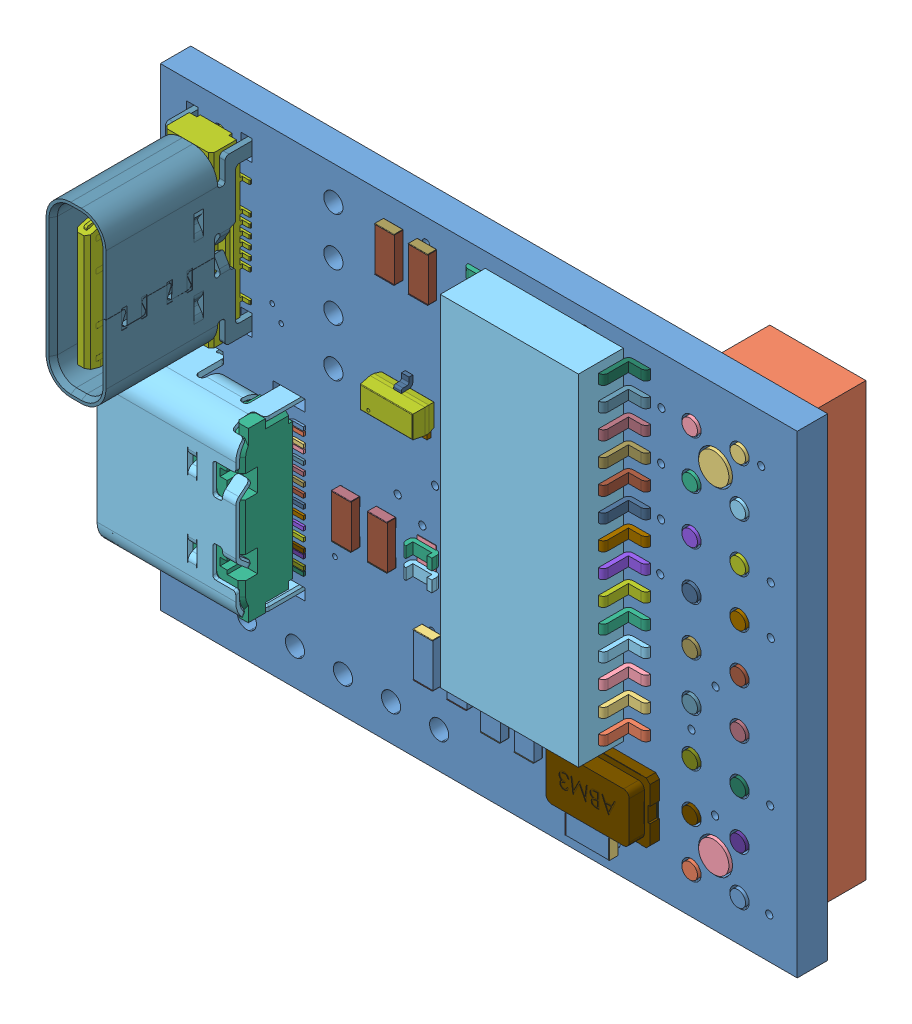
SolidWorks assembly pic backpack, configuration Default. Lengths in mm.
Overall size (33.69 32.08 21.86).
214 component instances, 150 part files, 0 mates.
Components (placement in the parent):
- Layer_1-1: Layer_1 [Predeterminado] at origin size (33.66 25.02 1.61)
- J1-1: J1 [Predeterminado] at (-14.605 24.638 -0.803) x (0 -1 0) z (0 0 -1) size (22.86 7.4 5.5)
  - Open CASCADE STEP translator 6.8 1.2.1-1: Open CASCADE STEP translator 6.8 1.2.1 [Predeterminado] at origin size (22.86 7.4 5.5)
    - Body_1-1: Body_1 [Predeterminado] at origin size (22.86 7.4 5.5)
      - =_[0_1_1_2]-1: =_[0_1_1_2] [Predeterminado] at (0 0 0.1) size (22.86 5.08 3.7)
      - =_[0_1_1_3]-1: =_[0_1_1_3] [Predeterminado] at origin size (21.14 7.4 0.1)
        - SOLID-1: SOLID [Predeterminado] at origin size (0.82 1.58 0.1)
        - SOLID_2-1: SOLID_2 [Predeterminado] at origin size (0.82 1.58 0.1)
        - SOLID_3-1: SOLID_3 [Predeterminado] at origin size (0.82 1.58 0.1)
        - SOLID_4-1: SOLID_4 [Predeterminado] at origin size (0.82 1.58 0.1)
        - SOLID_5-1: SOLID_5 [Predeterminado] at origin size (0.82 1.58 0.1)
        - SOLID_6-1: SOLID_6 [Predeterminado] at origin size (0.82 1.58 0.1)
        - SOLID_7-1: SOLID_7 [Predeterminado] at origin size (0.82 1.58 0.1)
        - SOLID_8-1: SOLID_8 [Predeterminado] at origin size (0.82 1.58 0.1)
        - SOLID_9-1: SOLID_9 [Predeterminado] at origin size (0.82 1.58 0.1)
        - SOLID_10-1: SOLID_10 [Predeterminado] at origin size (0.82 1.58 0.1)
        - SOLID_11-1: SOLID_11 [Predeterminado] at origin size (0.82 1.58 0.1)
        - SOLID_12-1: SOLID_12 [Predeterminado] at origin size (0.82 1.58 0.1)
        - SOLID_13-1: SOLID_13 [Predeterminado] at origin size (0.82 1.58 0.1)
        - SOLID_14-1: SOLID_14 [Predeterminado] at origin size (0.82 1.58 0.1)
        - SOLID_15-1: SOLID_15 [Predeterminado] at origin size (0.82 1.58 0.1)
        - SOLID_16-1: SOLID_16 [Predeterminado] at origin size (0.82 1.58 0.1)
        - SOLID_17-1: SOLID_17 [Predeterminado] at origin size (0.82 1.58 0.1)
        - SOLID_18-1: SOLID_18 [Predeterminado] at origin size (0.82 1.58 0.1)
      - =_[0_1_1_4]-1: =_[0_1_1_4] [Predeterminado] at origin size (21.14 3.36 1.8)
        - SOLID_19-1: SOLID_19 [Predeterminado] at origin size (0.82 0.82 1.8)
        - SOLID_20-1: SOLID_20 [Predeterminado] at origin size (0.82 0.82 1.8)
        - SOLID_21-1: SOLID_21 [Predeterminado] at origin size (0.82 0.82 1.8)
        - SOLID_22-1: SOLID_22 [Predeterminado] at origin size (0.82 0.82 1.8)
        - SOLID_23-1: SOLID_23 [Predeterminado] at origin size (0.82 0.82 1.8)
        - SOLID_24-1: SOLID_24 [Predeterminado] at origin size (0.82 0.82 1.8)
        - SOLID_25-1: SOLID_25 [Predeterminado] at origin size (0.82 0.82 1.8)
        - SOLID_26-1: SOLID_26 [Predeterminado] at origin size (0.82 0.82 1.8)
        - SOLID_27-1: SOLID_27 [Predeterminado] at origin size (0.82 0.82 1.8)
        - SOLID_28-1: SOLID_28 [Predeterminado] at origin size (0.82 0.82 1.8)
        - SOLID_29-1: SOLID_29 [Predeterminado] at origin size (0.82 0.82 1.8)
        - SOLID_30-1: SOLID_30 [Predeterminado] at origin size (0.82 0.82 1.8)
        - SOLID_31-1: SOLID_31 [Predeterminado] at origin size (0.82 0.82 1.8)
        - SOLID_32-1: SOLID_32 [Predeterminado] at origin size (0.82 0.82 1.8)
        - SOLID_33-1: SOLID_33 [Predeterminado] at origin size (0.82 0.82 1.8)
        - SOLID_34-1: SOLID_34 [Predeterminado] at origin size (0.82 0.82 1.8)
        - SOLID_35-1: SOLID_35 [Predeterminado] at origin size (0.82 0.82 1.8)
        - SOLID_36-1: SOLID_36 [Predeterminado] at origin size (0.82 0.82 1.8)
        - SOLID_37-1: SOLID_37 [Predeterminado] at origin size (1.6 1.6 1.8)
        - SOLID_38-1: SOLID_38 [Predeterminado] at origin size (1.6 1.6 1.8)
- U1-1: U1 [Predeterminado] at (-27.559 28.448 0.803) size (9.65 18 2.64)
  - Open CASCADE STEP translator 6.8 1.3.1-1: Open CASCADE STEP translator 6.8 1.3.1 [Predeterminado] at origin size (9.65 18 2.64)
    - Body_1-1: Body_1 [Predeterminado] at origin size (7.3 18 2.38)
    - Pin_1-1: Pin_1 [Predeterminado] at origin size (1.17 0.51 1.58)
    - Pin_2-1: Pin_2 [Predeterminado] at origin size (1.17 0.51 1.58)
    - Pin_3-1: Pin_3 [Predeterminado] at origin size (1.17 0.51 1.58)
    - Pin_4-1: Pin_4 [Predeterminado] at origin size (1.17 0.51 1.58)
    - Pin_5-1: Pin_5 [Predeterminado] at origin size (1.17 0.51 1.58)
    - Pin_6-1: Pin_6 [Predeterminado] at origin size (1.17 0.51 1.58)
    - Pin_7-1: Pin_7 [Predeterminado] at origin size (1.17 0.51 1.58)
    - Pin_8-1: Pin_8 [Predeterminado] at origin size (1.17 0.51 1.58)
    - Pin_9-1: Pin_9 [Predeterminado] at origin size (1.17 0.51 1.58)
    - Pin_10-1: Pin_10 [Predeterminado] at origin size (1.17 0.51 1.58)
    - Pin_11-1: Pin_11 [Predeterminado] at origin size (1.17 0.51 1.58)
    - Pin_12-1: Pin_12 [Predeterminado] at origin size (1.17 0.51 1.58)
    - Pin_13-1: Pin_13 [Predeterminado] at origin size (1.17 0.51 1.58)
    - Pin_14-1: Pin_14 [Predeterminado] at origin size (1.17 0.51 1.58)
    - Pin_15-1: Pin_15 [Predeterminado] at (18.8 -17.78 0) x (-1 0 0) z (0 0 1) size (1.17 0.51 1.58)
    - Pin_16-1: Pin_16 [Predeterminado] at (18.8 -15.24 0) x (-1 0 0) z (0 0 1) size (1.17 0.51 1.58)
    - Pin_17-1: Pin_17 [Predeterminado] at (18.8 -12.7 0) x (-1 0 0) z (0 0 1) size (1.17 0.51 1.58)
    - Pin_18-1: Pin_18 [Predeterminado] at (18.8 -10.16 0) x (-1 0 0) z (0 0 1) size (1.17 0.51 1.58)
    - Pin_19-1: Pin_19 [Predeterminado] at (18.8 -7.62 0) x (-1 0 0) z (0 0 1) size (1.17 0.51 1.58)
    - Pin_20-1: Pin_20 [Predeterminado] at (18.8 -5.08 0) x (-1 0 0) z (0 0 1) size (1.17 0.51 1.58)
    - Pin_21-1: Pin_21 [Predeterminado] at (18.8 -2.54 0) x (-1 0 0) z (0 0 1) size (1.17 0.51 1.58)
    - Pin_22-1: Pin_22 [Predeterminado] at (18.8 0 0) x (-1 0 0) z (0 0 1) size (1.17 0.51 1.58)
    - Pin_23-1: Pin_23 [Predeterminado] at (18.8 2.54 0) x (-1 0 0) z (0 0 1) size (1.17 0.51 1.58)
    - Pin_24-1: Pin_24 [Predeterminado] at (18.8 5.08 0) x (-1 0 0) z (0 0 1) size (1.17 0.51 1.58)
    - Pin_25-1: Pin_25 [Predeterminado] at (18.8 7.62 0) x (-1 0 0) z (0 0 1) size (1.17 0.51 1.58)
    - Pin_26-1: Pin_26 [Predeterminado] at (18.8 10.16 0) x (-1 0 0) z (0 0 1) size (1.17 0.51 1.58)
    - Pin_27-1: Pin_27 [Predeterminado] at (18.8 12.7 0) x (-1 0 0) z (0 0 1) size (1.17 0.51 1.58)
    - Pin_28-1: Pin_28 [Predeterminado] at (18.8 15.24 0) x (-1 0 0) z (0 0 1) size (1.17 0.51 1.58)
- U2-1: U2 [Predeterminado] at (-20.066 16.383 0.803) x (-1 0 0) z (0 0 1) size (5 3.22 1.3)
  - Open CASCADE STEP translator 6.8 1.4.1-1: Open CASCADE STEP translator 6.8 1.4.1 [Predeterminado] at origin size (5 3.22 1.3)
    - Body_1_2-1: Body_1_2 [Predeterminado] at (0 0 0.25) x (1 0 0) z (0 -1 0) size (5 1.3 3.22)
      - =_[0_1_1_3]-1: =_[0_1_1_3] [Predeterminado] at origin size (1.25 0.05 2)
      - =_[0_1_1_4]-1: =_[0_1_1_4] [Predeterminado] at origin size (1.25 0.05 2)
      - =_[0_1_1_5]-1: =_[0_1_1_5] [Predeterminado] at origin size (5 1.3 3.22)
- C2-1: C2 [Predeterminado] at (-26.035 17.907 0.803) x (0 -1 0) z (0 0 1) size (2.34 1.04 0.5)
  - Open CASCADE STEP translator 6.8 1.5.1-1: Open CASCADE STEP translator 6.8 1.5.1 [Predeterminado] at origin size (2.34 1.04 0.5)
    - Body_1_2-1: Body_1_2 [Predeterminado] at origin size (2.29 1.04 0.43)
    - Pin_1_2-1: Pin_1_2 [Predeterminado] at (0.3048 0 0) x (-1 0 0) z (0 0 1) size (0.51 1.02 0.5)
    - Pin_2_2-1: Pin_2_2 [Predeterminado] at origin size (0.51 1.02 0.5)
- C4-1: C4 [Predeterminado] at (-29.591 16.383 0.803) x (0 1 0) z (0 0 1) size (2.34 1.04 0.5)
  - Open CASCADE STEP translator 6.8 1.5.1-1: Open CASCADE STEP translator 6.8 1.5.1 [Predeterminado] at origin size (2.34 1.04 0.5)
    - Body_1_2-1: Body_1_2 [Predeterminado] at origin size (2.29 1.04 0.43)
    - Pin_1_2-1: Pin_1_2 [Predeterminado] at (0.3048 0 0) x (-1 0 0) z (0 0 1) size (0.51 1.02 0.5)
    - Pin_2_2-1: Pin_2_2 [Predeterminado] at origin size (0.51 1.02 0.5)
- C5-1: C5 [Predeterminado] at (-21.971 13.716 0.803) size (2.34 1.04 0.5)
  - Open CASCADE STEP translator 6.8 1.5.1-1: Open CASCADE STEP translator 6.8 1.5.1 [Predeterminado] at origin size (2.34 1.04 0.5)
    - Body_1_2-1: Body_1_2 [Predeterminado] at origin size (2.29 1.04 0.43)
    - Pin_1_2-1: Pin_1_2 [Predeterminado] at (0.3048 0 0) x (-1 0 0) z (0 0 1) size (0.51 1.02 0.5)
    - Pin_2_2-1: Pin_2_2 [Predeterminado] at origin size (0.51 1.02 0.5)
- C1-1: C1 [Predeterminado] at (-24.257 17.8816 0.803) x (0 -1 0) z (0 0 1) size (2.34 1.04 0.5)
  - Open CASCADE STEP translator 6.8 1.5.1-1: Open CASCADE STEP translator 6.8 1.5.1 [Predeterminado] at origin size (2.34 1.04 0.5)
    - Body_1_2-1: Body_1_2 [Predeterminado] at origin size (2.29 1.04 0.43)
    - Pin_1_2-1: Pin_1_2 [Predeterminado] at (0.3048 0 0) x (-1 0 0) z (0 0 1) size (0.51 1.02 0.5)
    - Pin_2_2-1: Pin_2_2 [Predeterminado] at origin size (0.51 1.02 0.5)
- C3-1: C3 [Predeterminado] at (-27.813 16.383 0.803) x (0 1 0) z (0 0 1) size (2.34 1.04 0.5)
  - Open CASCADE STEP translator 6.8 1.5.1-1: Open CASCADE STEP translator 6.8 1.5.1 [Predeterminado] at origin size (2.34 1.04 0.5)
    - Body_1_2-1: Body_1_2 [Predeterminado] at origin size (2.29 1.04 0.43)
    - Pin_1_2-1: Pin_1_2 [Predeterminado] at (0.3048 0 0) x (-1 0 0) z (0 0 1) size (0.51 1.02 0.5)
    - Pin_2_2-1: Pin_2_2 [Predeterminado] at origin size (0.51 1.02 0.5)
- JP1-1: JP1 [Predeterminado] at (-29.845 21.082 0.803) x (0 1 0) z (0 0 1) size (2 1.5 0.63)
  - Open CASCADE STEP translator 6.8 1.11.1-1: Open CASCADE STEP translator 6.8 1.11.1 [Predeterminado] at origin size (2 1.5 0.63)
    - Body_1_4-1: Body_1_4 [Predeterminado] at origin size (2 1 0.03)
    - Pin_1_3-1: Pin_1_3 [Predeterminado] x (0 1 0) z (0 0 1) size (1.5 0.59 0.63)
    - Pin_2_3-1: Pin_2_3 [Predeterminado] at (1 -1 0) x (0 1 0) z (0 0 1) size (1.5 0.59 0.63)
- Q1-1: Q1 [Predeterminado] at (-30.8 28.559 0.803) x (0 1 0) z (0 0 1) size (2.4 2.9 1.2)
  - Open CASCADE STEP translator 6.8 1.12.1-1: Open CASCADE STEP translator 6.8 1.12.1 [Predeterminado] at origin size (2.4 2.9 1.2)
    - Body_1_3-1: Body_1_3 [Predeterminado] at origin size (2.4 2.9 1.2)
      - =_[0_1_1_2]_2-1: =_[0_1_1_2]_2 [Predeterminado] at origin size (1.3 2.9 1.15)
      - =_[0_1_1_3]_2-1: =_[0_1_1_3]_2 [Predeterminado] at origin size (0.55 2.3 0.61)
        - SOLID_39-1: SOLID_39 [Predeterminado] at origin size (0.55 0.4 0.61)
        - SOLID_40-1: SOLID_40 [Predeterminado] at origin size (0.55 0.4 0.61)
      - =_[0_1_1_4]_2-1: =_[0_1_1_4]_2 [Predeterminado] at origin size (0.55 0.4 0.61)
- R1-1: R1 [Predeterminado] at (-29.845 36.0426 0.803) x (0 -1 0) z (0 0 1) size (2.34 1.04 0.5)
  - Open CASCADE STEP translator 6.8 1.13.1-1: Open CASCADE STEP translator 6.8 1.13.1 [Predeterminado] at origin size (2.34 1.04 0.5)
    - Body_1_5-1: Body_1_5 [Predeterminado] at origin size (2.29 1.04 0.43)
    - Pin_1_4-1: Pin_1_4 [Predeterminado] at (0.3048 0 0) x (-1 0 0) z (0 0 1) size (0.51 1.02 0.5)
    - Pin_2_4-1: Pin_2_4 [Predeterminado] at origin size (0.51 1.02 0.5)
- R2-1: R2 [Predeterminado] at (-31.623 36.068 0.803) x (0 -1 0) z (0 0 1) size (2.34 1.04 0.5)
  - Open CASCADE STEP translator 6.8 1.13.1-1: Open CASCADE STEP translator 6.8 1.13.1 [Predeterminado] at origin size (2.34 1.04 0.5)
    - Body_1_5-1: Body_1_5 [Predeterminado] at origin size (2.29 1.04 0.43)
    - Pin_1_4-1: Pin_1_4 [Predeterminado] at (0.3048 0 0) x (-1 0 0) z (0 0 1) size (0.51 1.02 0.5)
    - Pin_2_4-1: Pin_2_4 [Predeterminado] at origin size (0.51 1.02 0.5)
- J4-1: J4 [Predeterminado] at (-39.3381 34.5271 0.803) x (0 -1 0) z (0 0 1) size (30.95 12.2 21.86)
  - Open CASCADE STEP translator 6.8 1.15.1-1: Open CASCADE STEP translator 6.8 1.15.1 [Predeterminado] at origin size (30.95 12.2 21.86)
    - Body_1_4-1: Body_1_4 [Predeterminado] at (2.8 -2.8 0.11) x (1 0 0) z (0 -1 0) size (30.95 21.86 12.2)
      - Imported-1: Imported [Predeterminado] at (22 -7.19 8.4402) x (-1 0 0) z (0 0.000001 1) size (8.94 8.16 3.49)
      - Imported-2: Imported [Predeterminado] at (72.395 48.5033 -3.3613) x (1 0 0) z (0 1 -0.000001) size (8.94 3.77 7.85)
        - SHELL-1: SHELL [Predeterminado] at origin size (0.19 0.16 0.35)
        - SHELL_2-1: SHELL_2 [Predeterminado] at origin size (0.26 0.3 0.35)
        - SHELL_3-1: SHELL_3 [Predeterminado] at origin size (0.26 0.31 0.35)
        - SHELL_4-1: SHELL_4 [Predeterminado] at origin size (0.3 0.16 0.3)
        - SHELL_5-1: SHELL_5 [Predeterminado] at origin size (0.3 0.16 0.3)
        - SHELL_6-1: SHELL_6 [Predeterminado] at origin size (0.48 0.17 0.48)
        - SHELL_7-1: SHELL_7 [Predeterminado] at origin size (0.48 0.17 0.48)
        - SHELL_8-1: SHELL_8 [Predeterminado] at origin size (0.16 0.5 0.5)
        - SHELL_9-1: SHELL_9 [Predeterminado] at origin size (0.16 0.5 0.5)
        - SHELL_10-1: SHELL_10 [Predeterminado] at origin size (0.19 0.16 0.35)
        - ASSEMBLY-1: ASSEMBLY [Predeterminado] at origin size (8.94 3.77 7.85)
          - SHELL_11-1: SHELL_11 [Predeterminado] at origin size (8.94 3.77 7.85)
          - SHELL_12-1: SHELL_12 [Predeterminado] at origin size (0.2 0.01 0)
          - SHELL_13-1: SHELL_13 [Predeterminado] at origin size (0.2 0.01 0)
          - SHELL_14-1: SHELL_14 [Predeterminado] at origin size (0.2 0.01 0)
        - SHELL_16-1: SHELL_16 [Predeterminado] at origin size (0.21 0.01 0.02)
        - SHELL_17-1: SHELL_17 [Predeterminado] at origin size (0.2 0 0.01)
        - SHELL_18-1: SHELL_18 [Predeterminado] at origin size (0.2 0.1 0.1)
        - SHELL_19-1: SHELL_19 [Predeterminado] at origin size (0.2 0.1 0.1)
        - SHELL_20-1: SHELL_20 [Predeterminado] at origin size (0.2 0.1 0.1)
        - SHELL_21-1: SHELL_21 [Predeterminado] at origin size (0.2 0.1 0.1)
- J5-1: J5 [Predeterminado] at (-36.576 24.384 0.803) x (0 -1 0) z (0 0 1) size (8.94 7.71 4.41)
  - Open CASCADE STEP translator 6.8 1.16.1-1: Open CASCADE STEP translator 6.8 1.16.1 [Predeterminado] at origin size (8.94 7.71 4.41)
    - Body_1_5-1: Body_1_5 [Predeterminado] at (3.2 -4.8 0) x (1 0 0) z (0 -1 0) size (8.94 4.41 7.71)
      - Imported_2-1: Imported_2 [Predeterminado] at (0 0 -1.255) size (8.94 4.41 7.71)
        - SOLID_41-1: SOLID_41 [Predeterminado] at origin size (0.25 0.05 2.38)
        - SOLID_42-1: SOLID_42 [Predeterminado] at origin size (0.25 0.05 2.38)
        - SOLID_43-1: SOLID_43 [Predeterminado] at origin size (0.25 0.05 1.88)
        - SOLID_44-1: SOLID_44 [Predeterminado] at origin size (0.25 0.05 1.88)
        - SOLID_45-1: SOLID_45 [Predeterminado] at origin size (0.25 0.05 1.88)
        - SOLID_46-1: SOLID_46 [Predeterminado] at origin size (0.25 0.05 1.88)
        - SOLID_47-1: SOLID_47 [Predeterminado] at origin size (0.25 0.05 1.88)
        - SOLID_48-1: SOLID_48 [Predeterminado] at origin size (0.25 0.05 1.88)
        - SOLID_49-1: SOLID_49 [Predeterminado] at origin size (0.25 0.05 1.88)
        - SOLID_50-1: SOLID_50 [Predeterminado] at origin size (0.25 0.05 1.88)
        - SOLID_51-1: SOLID_51 [Predeterminado] at origin size (0.25 0.05 2.38)
        - SOLID_52-1: SOLID_52 [Predeterminado] at origin size (0.25 0.05 2.38)
        - SOLID_53-1: SOLID_53 [Predeterminado] at origin size (0.25 0.05 2.38)
        - SOLID_54-1: SOLID_54 [Predeterminado] at origin size (0.25 0.05 1.88)
        - SOLID_55-1: SOLID_55 [Predeterminado] at origin size (0.25 0.05 1.88)
        - SOLID_56-1: SOLID_56 [Predeterminado] at origin size (0.25 0.05 2.38)
        - SOLID_57-1: SOLID_57 [Predeterminado] at origin size (0.25 0.05 1.88)
        - SOLID_58-1: SOLID_58 [Predeterminado] at origin size (0.25 0.05 1.88)
        - SOLID_59-1: SOLID_59 [Predeterminado] at origin size (0.25 0.05 1.88)
        - SOLID_60-1: SOLID_60 [Predeterminado] at origin size (0.25 0.05 1.88)
        - SOLID_61-1: SOLID_61 [Predeterminado] at origin size (0.25 0.05 2.38)
        - SOLID_62-1: SOLID_62 [Predeterminado] at origin size (0.25 0.05 1.88)
        - SOLID_63-1: SOLID_63 [Predeterminado] at origin size (0.25 0.05 1.88)
        - SOLID_64-1: SOLID_64 [Predeterminado] at origin size (0.25 0.05 2.38)
        - SOLID_65-1: SOLID_65 [Predeterminado] at origin size (0.35 0.1 1.82)
        - SOLID_66-1: SOLID_66 [Predeterminado] at origin size (0.35 0.1 1.82)
        - SOLID_67-1: SOLID_67 [Predeterminado] at origin size (0.2 0.32 0.73)
        - SOLID_68-1: SOLID_68 [Predeterminado] at origin size (0.2 0.32 0.73)
        - SOLID_69-1: SOLID_69 [Predeterminado] at origin size (0.2 0.32 0.73)
        - SOLID_70-1: SOLID_70 [Predeterminado] at origin size (0.2 0.32 0.73)
        - SOLID_71-1: SOLID_71 [Predeterminado] at origin size (0.2 0.32 0.73)
        - SOLID_72-1: SOLID_72 [Predeterminado] at origin size (0.2 0.32 0.73)
        - SOLID_73-1: SOLID_73 [Predeterminado] at origin size (0.2 0.32 0.73)
        - SOLID_74-1: SOLID_74 [Predeterminado] at origin size (0.2 0.32 0.73)
        - SOLID_75-1: SOLID_75 [Predeterminado] at origin size (0.2 0.32 0.73)
        - SOLID_76-1: SOLID_76 [Predeterminado] at origin size (0.2 0.32 0.73)
        - SOLID_77-1: SOLID_77 [Predeterminado] at origin size (0.2 0.32 0.73)
        - SOLID_78-1: SOLID_78 [Predeterminado] at origin size (0.2 0.32 0.73)
        - SOLID_79-1: SOLID_79 [Predeterminado] at origin size (0.2 0.32 0.73)
        - SOLID_80-1: SOLID_80 [Predeterminado] at origin size (0.2 0.32 0.73)
        - SOLID_81-1: SOLID_81 [Predeterminado] at origin size (0.2 0.32 0.73)
        - SOLID_82-1: SOLID_82 [Predeterminado] at origin size (0.2 0.32 0.73)
        - SOLID_83-1: SOLID_83 [Predeterminado] at origin size (8.94 4.41 7.34)
        - SOLID_84-1: SOLID_84 [Predeterminado] at origin size (8.89 3.61 6.57)
- R3-1: R3 [Predeterminado] at (-33.909 20.574 0.803) x (0 1 0) z (0 0 1) size (2.34 1.04 0.5)
  - Open CASCADE STEP translator 6.8 1.13.1-1: Open CASCADE STEP translator 6.8 1.13.1 [Predeterminado] at origin size (2.34 1.04 0.5)
    - Body_1_5-1: Body_1_5 [Predeterminado] at origin size (2.29 1.04 0.43)
    - Pin_1_4-1: Pin_1_4 [Predeterminado] at (0.3048 0 0) x (-1 0 0) z (0 0 1) size (0.51 1.02 0.5)
    - Pin_2_4-1: Pin_2_4 [Predeterminado] at origin size (0.51 1.02 0.5)
- R4-1: R4 [Predeterminado] at (-32.004 20.574 0.803) x (0 1 0) z (0 0 1) size (2.34 1.04 0.5)
  - Open CASCADE STEP translator 6.8 1.13.1-1: Open CASCADE STEP translator 6.8 1.13.1 [Predeterminado] at origin size (2.34 1.04 0.5)
    - Body_1_5-1: Body_1_5 [Predeterminado] at origin size (2.29 1.04 0.43)
    - Pin_1_4-1: Pin_1_4 [Predeterminado] at (0.3048 0 0) x (-1 0 0) z (0 0 1) size (0.51 1.02 0.5)
    - Pin_2_4-1: Pin_2_4 [Predeterminado] at origin size (0.51 1.02 0.5)
